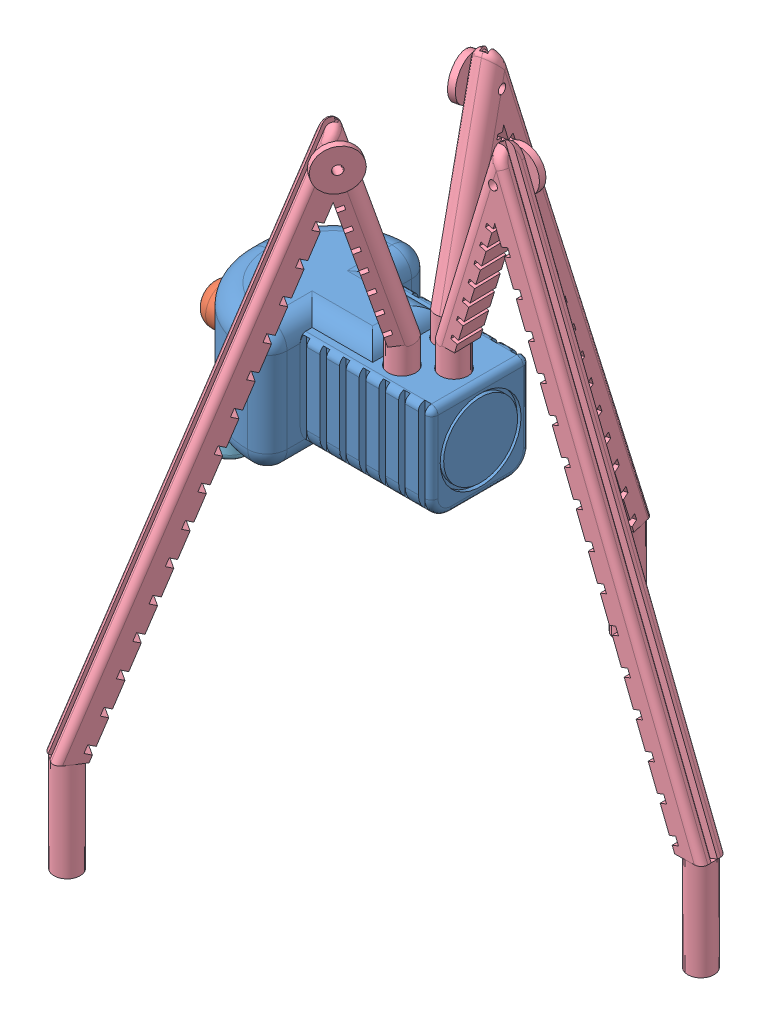
SolidWorks assembly sbor1, configuration Default. Lengths in mm.
Overall size (72.2 94.61 79.73).
8 component instances, 5 part files, 17 mates.
Components (placement in the parent):
- body-1: body [По умолчанию] at origin size (35 19 25)
- glaz-1: glaz [По умолчанию] at (-19.9 12 6) x (0 1 0) z (0 0 1) size (6 5 6)
- glaz-2: glaz [По умолчанию] at (-19.9 12 -6) x (0 0.381849 -0.924225) z (0 0.924225 0.381849) size (6 5 6)
- dwear-1: dwear [По умолчанию] at (-19.9612 -6.8 0.2491) x (0.054752 0 0.9985) z (-0.9985 0 0.054752) size (2.16 10 5)
- noga-1: noga [По умолчанию] at (-1.1665 19 4.1887) x (0.544447 0 -0.838795) z (0 -1 0) size (40.9 5.04 94.61)
- noga-2: noga [По умолчанию] at (3.0759 19 -6.0128) x (0.234222 0 0.972183) z (0 -1 0) size (40.9 5.04 94.61)
- noga-3: noga [По умолчанию] at (8.0398 19 2.01) x (-0.999798 0 0.020085) z (0 -1 0) size (40.9 5.04 94.61)
- wear-1: wear [По умолчанию] at (-21.9639 -6.1 0.2542) x (0.054752 0 0.9985) z (0 -1 0) size (12 5 6)
Mates (geometry in assembly coordinates):
- Совпадение12: coincident anti-aligned: plane of body-1 through (1.6 4 -3.6) normal (0 1 0); plane of noga-2 through (1.6 4 -3.6) normal (0 -1 0)
- Концентричный5: concentric anti-aligned: circle of body-1; circle of noga-2
- Совпадение13: coincident anti-aligned: plane of body-1 through (1.6 4 3.6) normal (0 1 0); plane of noga-1 through (1.6 4 3.6) normal (0 -1 0)
- Концентричный7: concentric anti-aligned: circle of body-1; circle of noga-1
- Совпадение14: coincident anti-aligned: plane of body-1 through (6 4 0.0506) normal (0 1 0); plane of noga-3 through (6 4 0.0506) normal (0 -1 0)
- Концентричный8: concentric anti-aligned: circle of body-1; circle of noga-3
- Касательность4: tangent aligned: plane of body-1 through (-19.9612 1.2 0.2491) normal (0 -1 0); sphere of dwear-1
- Концентричный11: concentric aligned: cylinder of body-1 through (-19.9612 1.2 0.2491) axis (0 -1 0) radius 1.1; cylinder of dwear-1 through (-19.9612 3.2 0.2491) axis (0 -1 0) radius 1
- Параллельность3: parallel aligned: plane of dwear-1 through (-24.0099 -5.2 -0.5304) normal (-0.9985 0 0.054752); plane of wear-1 through (-23.9609 -6.1 0.3637) normal (-0.9985 0 0.054752)
- Совпадение17: coincident anti-aligned: plane of dwear-1 through (-19.9612 -5.2 0.2491) normal (0 1 0); plane of wear-1 through (-27.0166 -5.2 -0.5704) normal (0 -1 0)
- Совпадение18: coincident aligned: plane of dwear-1 through (-24.0099 -5.2 -0.5304) normal (-0.9985 0 0.054752); plane of wear-1 through (-23.9609 -6.1 0.3637) normal (-0.9985 0 0.054752)
- Совпадение19: coincident anti-aligned: plane of dwear-1 through (-19.9067 -5.2 1.243) normal (0.054752 0 0.9985); plane of wear-1 through (-26.8961 -5.2 1.6263) normal (-0.054752 0 -0.9985)
- Совпадение20: coincident anti-aligned: plane of body-1 through (-19.9 12 -6) normal (-1 0 0); plane of glaz-1 through (-19.9 12 6) normal (1 0 0)
- Концентричный13: concentric aligned: circle of body-1; circle of glaz-2
- Совпадение21: coincident anti-aligned: plane of body-1 through (-19.9 12 -6) normal (-1 0 0); plane of glaz-2 through (-19.9 12 -6) normal (1 0 0)
- Параллельность4: parallel anti-aligned: plane of body-1 through (-19.9 12 6) normal (-1 0 0); plane of glaz-1 through (-19.9 12 6) normal (1 0 0)
- Концентричный14: concentric aligned: circle of body-1; circle of glaz-1
